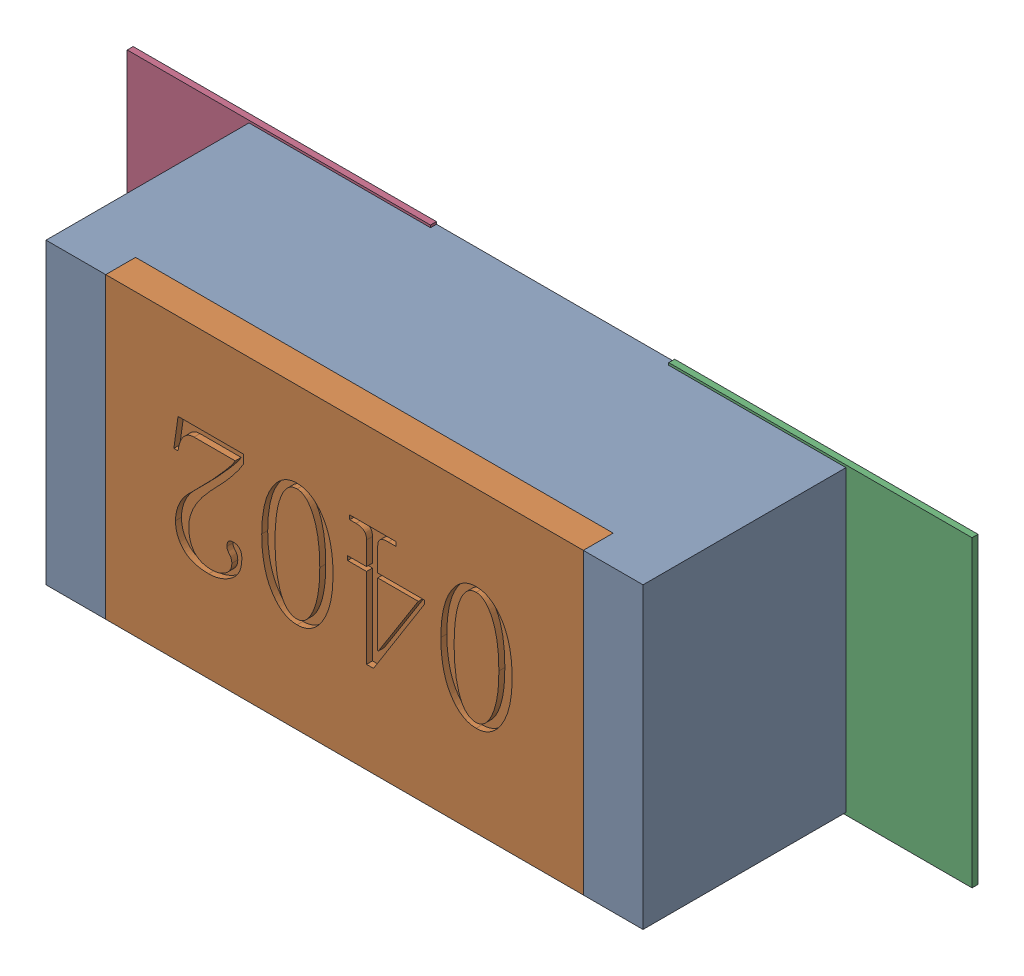
SolidWorks assembly R18, configuration Défaut. Lengths in mm.
Overall size (1.42 0.51 0.35).
5 component instances, 2 part files, 0 mates.
Components (placement in the parent):
- R0402-1: R0402 [Défaut] at (51.9938 -10.1473 0) x (-1 0 0) z (0 0 1) size (1 0.5 0.35)
- 6504207776-1: 6504207776 [Défaut] at (52.4509 -10.1474 0) size (0.51 0.51 0.01)
  - Extruded-1: Extruded [Défaut] at origin size (0.51 0.51 0.01)
- 6504207776-2: 6504207776 [Défaut] at (51.5438 -10.1474 0) size (0.51 0.51 0.01)
  - Extruded-1: Extruded [Défaut] at origin size (0.51 0.51 0.01)
